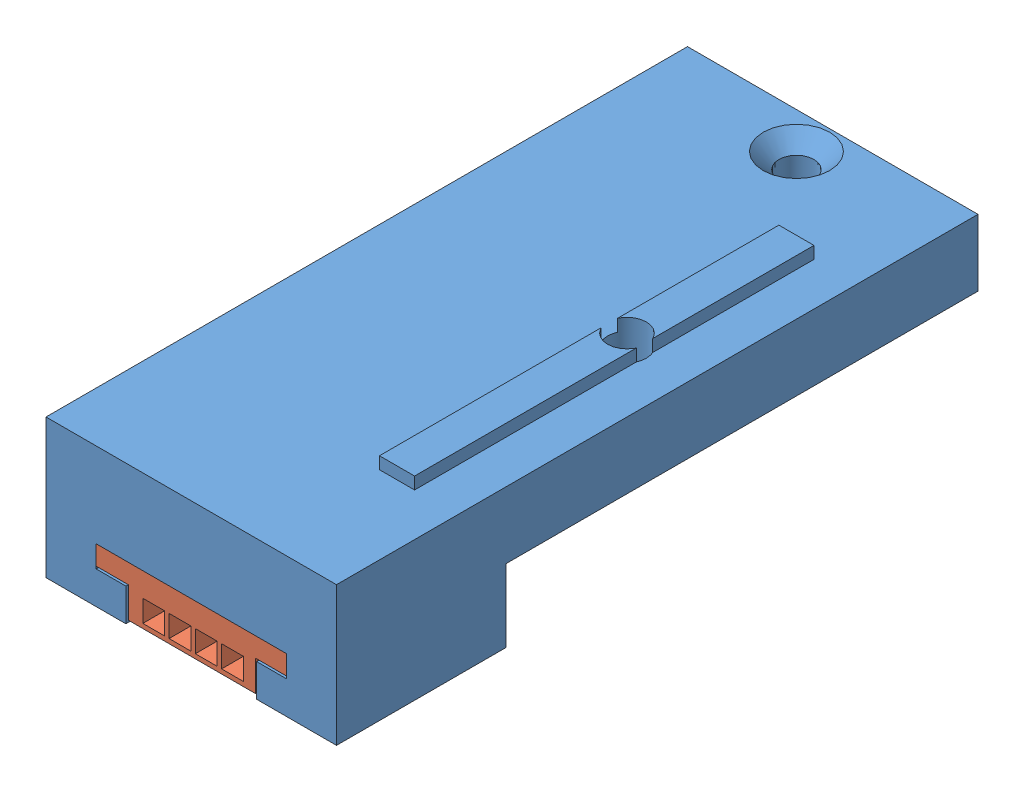
SolidWorks assembly tcs34725BoardAndSupport, configuration Default. Lengths in mm.
Overall size (24 18.14 53).
2 component instances, 2 part files, 3 mates.
Components (placement in the parent):
- tcs34725Support-1: tcs34725Support [Default] at (8.0281 22.7578 15.5427) size (24 12.5 53)
- tcs34725Board-1: tcs34725Board [Default] at (8.0281 27.2578 44.4427) x (0 0 -1) z (0 -1 0) size (48.2 15.7 12)
Mates (geometry in assembly coordinates):
- Coincident4: coincident aligned: plane of tcs34725Support-1 through (8.0281 22.7578 68.5427) normal (0 0 1); plane of tcs34725Board-1 through (15.8781 25.6578 68.5427) normal (0 0 1)
- Coincident5: coincident anti-aligned: plane of tcs34725Support-1 through (0.1781 27.2578 68.5427) normal (1 0 0); plane of tcs34725Board-1 through (0.1781 25.6578 68.5427) normal (-1 0 0)
- Coincident6: coincident anti-aligned: plane of tcs34725Support-1 through (15.8781 27.2578 68.5427) normal (0 -1 0); plane of tcs34725Board-1 through (8.0281 27.2578 44.4427) normal (0 1 0)
